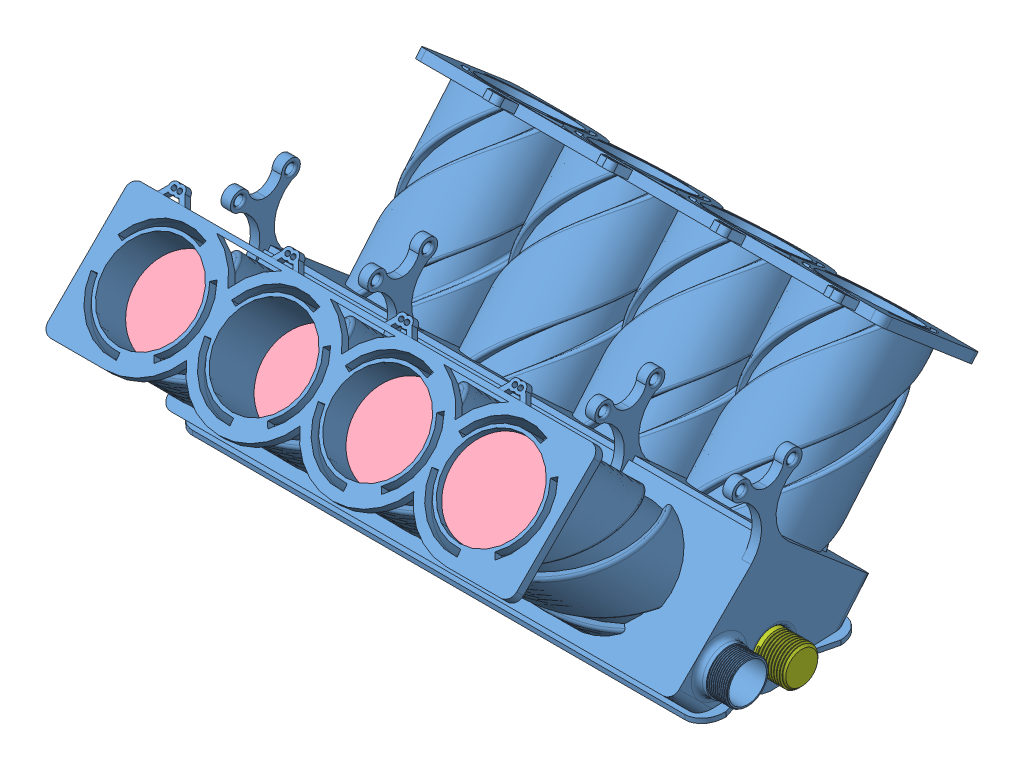
SolidWorks assembly Full Crank, configuration Default. Lengths in mm.
Overall size (601.48 350.14 484.53).
151 component instances, 27 part files, 63 mates.
Components (placement in the parent):
- exhuast Left-1: exhuast Left [Default<As Machined>] at (-44.5302 479.4245 -557.6035) x (1 0 0) z (0 0.648313 0.761374) size (550 292.5 196.99) (hidden)
- exhuast Right-1: exhuast Right [Default<As Machined>] at (-105.0302 606.7426 -177.23) x (1 0 0) z (0 -0.707107 0.707107) size (550 292.5 196.99) (hidden)
- Engine full-1: Engine full [Default] at (257.949 54.9062 -9.1227) x (-1 0 0) z (0 0.079946 -0.996799) size (581.5 289.56 459.4)
- AirRailsFinal-1: AirRailsFinal [Default] at (-30.5697 195.6323 -202.0466) x (1 0 0) z (0 0 1) size (435.48 82.44 318.32) (hidden)
- supercharger-1: supercharger [Default] at (314.7583 907.7189 -431.8002) x (0 0 1) z (0 -1 0) size (226 539.76 151) (hidden)
  - casing-1: casing [Default] at (105.1186 33.7762 242.5866) size (226 360 151)
  - cork screw one-1: cork screw one [Default] at (180.1186 333.7762 242.5866) x (0.113215 0 0.993571) z (-0.993571 0 0.113215) size (101.97 371 100.73)
  - cork screw two-1: cork screw two [Default] at (105.1186 33.7762 242.5866) x (-0.675443 0 -0.737412) z (0.737412 0 -0.675443) size (99.6 341 99.85)
  - LidOne-1: LidOne [Default] at (180.1186 28.7762 242.5866) x (-1 0 0) z (0 0 1) size (226 23.47 151)
  - heligearAntiClockwise-1: heligearAntiClockwise [Default] at (180.1186 339.7762 242.5866) x (-0.760972 0 0.648785) z (-0.648785 0 -0.760972) size (76.65 15 76.65)
  - heligearClockwise-1: heligearClockwise [Default] at (105.1186 339.7762 242.5866) x (-0.120243 0 0.992744) z (-0.992744 0 -0.120243) size (76.65 15 76.65)
  - axle support-2: axle support [Default] at (126.5104 354.7762 251.6132) size (28.48 5 80.98)
  - heligearAntiClockwise 38mm-1: heligearAntiClockwise 38mm [Default] at (180.1186 359.7762 242.5866) x (0.451037 0 0.892505) z (-0.892505 0 0.451037) size (40.05 20 40.06)
  - heligearClockwise 38mm-1: heligearClockwise 38mm [Default] at (142.6186 359.7762 242.5885) x (0.774286 0 0.632836) z (-0.632836 0 0.774286) size (40.05 15 40.06)
  - PTaxle-1: PTaxle [Default] at (142.6186 357.7762 242.5885) x (0.987746 0 -0.156068) z (0.156068 0 0.987746) size (25 190.76 25)
  - LidGearSide-1: LidGearSide [Default] at (105.1186 388.7762 242.5866) size (226 108.1 151)
  - long bolts-20: long bolts [Default] at (79.8615 14.7762 303.5627) x (0 1 0) z (0 0 1) size (388.15 12.67 12.66)
  - long bolts-21: long bolts [Default] at (226.7877 14.7762 195.9176) x (0 1 0) z (0 0 1) size (388.15 12.67 12.66)
  - long bolts-22: long bolts [Default] at (205.3757 14.7762 181.6106) x (0 1 0) z (0 0 1) size (388.15 12.67 12.66)
  - long bolts-23: long bolts [Default] at (180.1186 14.7762 176.5866) x (0 1 0) z (0 0 1) size (388.15 12.67 12.66)
  - long bolts-24: long bolts [Default] at (105.1186 14.7762 176.5866) x (0 1 0) z (0 0 1) size (388.15 12.67 12.66)
  - long bolts-25: long bolts [Default] at (79.8615 14.7762 181.6106) x (0 1 0) z (0 0 1) size (388.15 12.67 12.66)
  - long bolts-26: long bolts [Default] at (58.4496 14.7762 195.9176) x (0 1 0) z (0 0 1) size (388.15 12.67 12.66)
  - long bolts-27: long bolts [Default] at (44.1426 14.7762 217.3295) x (0 1 0) z (0 0 1) size (388.15 12.67 12.66)
  - long bolts-28: long bolts [Default] at (39.1186 14.7762 242.5866) x (0 1 0) z (0 0 1) size (388.15 12.67 12.66)
  - long bolts-29: long bolts [Default] at (44.1426 14.7762 267.8437) x (0 1 0) z (0 0 1) size (388.15 12.67 12.66)
  - long bolts-30: long bolts [Default] at (58.4496 14.7762 289.2557) x (0 1 0) z (0 0 1) size (388.15 12.67 12.66)
  - long bolts-32: long bolts [Default] at (241.0947 14.7762 217.3295) x (0 1 0) z (0.991179 0 -0.132529) size (388.15 12.67 12.66)
  - long bolts-33: long bolts [Default] at (246.1186 14.7762 242.5866) x (0 1 0) z (0.903937 0 0.427666) size (388.15 12.67 12.66)
  - long bolts-34: long bolts [Default] at (241.0947 14.7762 267.8437) x (0 1 0) z (-0.949196 0 -0.314684) size (388.15 12.67 12.66)
  - long bolts-35: long bolts [Default] at (226.7877 14.7762 289.2557) x (0 1 0) z (-0.597909 0 0.801564) size (388.15 12.67 12.66)
  - long bolts-36: long bolts [Default] at (205.3757 14.7762 303.5627) x (0 1 0) z (-0.95126 0 -0.308391) size (388.15 12.67 12.66)
  - Nut 6mm-17: Nut 6mm [Default] at (205.3757 17.7762 303.5627) size (12 6 13.86)
  - Nut 6mm-18: Nut 6mm [Default] at (226.7877 17.7762 289.2557) size (12 6 13.86)
  - Nut 6mm-20: Nut 6mm [Default] at (241.0947 17.7762 217.3295) size (12 6 13.86)
  - Nut 6mm-21: Nut 6mm [Default] at (226.7877 17.7762 195.9176) size (12 6 13.86)
  - Nut 6mm-22: Nut 6mm [Default] at (241.0947 17.7762 267.8437) x (0.907106 0 -0.420902) z (0.420902 0 0.907106) size (12 6 13.86)
  - Nut 6mm-23: Nut 6mm [Default] at (246.1186 17.7762 242.5866) size (12 6 13.86)
  - Nut 6mm-24: Nut 6mm [Default] at (205.3757 17.7762 181.6106) size (12 6 13.86)
  - Nut 6mm-25: Nut 6mm [Default] at (105.1186 17.7762 176.5866) size (12 6 13.86)
  - Nut 6mm-26: Nut 6mm [Default] at (180.1186 17.7762 176.5866) size (12 6 13.86)
  - Nut 6mm-27: Nut 6mm [Default] at (79.8615 17.7762 303.5627) size (12 6 13.86)
  - Nut 6mm-29: Nut 6mm [Default] at (44.1426 17.7762 217.3295) size (12 6 13.86)
  - Nut 6mm-30: Nut 6mm [Default] at (79.8615 17.7762 181.6106) size (12 6 13.86)
  - Nut 6mm-31: Nut 6mm [Default] at (58.4496 17.7762 195.9176) size (12 6 13.86)
  - Nut 6mm-32: Nut 6mm [Default] at (44.1426 17.7762 267.8437) size (12 6 13.86)
  - Nut 6mm-33: Nut 6mm [Default] at (39.1186 17.7762 242.5866) size (12 6 13.86)
  - Nut 6mm-34: Nut 6mm [Default] at (58.4496 17.7762 289.2557) size (12 6 13.86)
- HeadASSEM-1: HeadASSEM [Default] at (236.3876 519.9383 1.112) x (-1 0 0) z (0 -0.648313 -0.761374) size (495 98 155) (hidden)
  - head-1: head [Default] at (-68.8322 296.3763 369.1572) size (495 90 155)
  - sparkplug-1: sparkplug [Default] at (38.6678 341.5148 336.6572) x (-0.837169 0 -0.546944) z (-0.546944 0 0.837169) size (16 84.49 18.48)
  - sparkplug-2: sparkplug [Default] at (158.6678 341.5148 336.6572) x (-0.837169 0 -0.546944) z (-0.546944 0 0.837169) size (16 84.49 18.48)
  - sparkplug-3: sparkplug [Default] at (278.6678 341.5148 336.6572) x (-0.837169 0 -0.546944) z (-0.546944 0 0.837169) size (16 84.49 18.48)
  - sparkplug-4: sparkplug [Default] at (-81.3322 341.5148 336.6572) x (-0.837169 0 -0.546944) z (-0.546944 0 0.837169) size (16 84.49 18.48)
  - campin-1: campin [Default] at (31.1678 376.3763 369.1572) x (-0.693491 0 -0.720466) z (0.720466 0 -0.693491) size (28 70 28)
  - campin-2: campin [Default] at (-48.8322 376.3763 369.1572) x (-0.717846 0 0.696202) z (-0.696202 0 -0.717846) size (28 70 28)
  - campin-3: campin [Default] at (151.1678 376.3763 369.1572) x (0.967975 0 -0.251048) z (0.251048 0 0.967975) size (28 70 28)
  - campin-4: campin [Default] at (71.1678 376.3763 369.1572) x (-0.768196 0 0.640214) z (-0.640214 0 -0.768196) size (28 70 28)
  - campin-6: campin [Default] at (-88.8322 376.3763 369.1572) x (0.884294 0 0.46693) z (-0.46693 0 0.884294) size (28 70 28)
  - campin-5: campin [Default] at (191.1678 376.3763 369.1572) x (0.919682 0 -0.392664) z (0.392664 0 0.919682) size (28 70 28)
  - campin-7: campin [Default] at (271.1678 376.3763 369.1572) x (0.288066 0 0.95761) z (-0.95761 0 0.288066) size (28 70 28)
  - campin-8: campin [Default] at (311.1678 376.3763 369.1572) x (0 0 1) z (-1 0 0) size (28 70 28)
  - cover-2: cover [Default] at (49.7609 309.3868 195.7023) size (495 63 135)
- HeadASSEM-2: HeadASSEM [Default] at (-25.948 543.3016 -582.4258) x (1 0 0) z (0 -0.707107 0.707107) size (495 98 155) (hidden)
  - head-1: head [Default] at (-68.8322 296.3763 369.1572) size (495 90 155)
  - sparkplug-1: sparkplug [Default] at (38.6678 341.5148 336.6572) x (-0.837169 0 -0.546944) z (-0.546944 0 0.837169) size (16 84.49 18.48)
  - sparkplug-2: sparkplug [Default] at (158.6678 341.5148 336.6572) x (-0.837169 0 -0.546944) z (-0.546944 0 0.837169) size (16 84.49 18.48)
  - sparkplug-3: sparkplug [Default] at (278.6678 341.5148 336.6572) x (-0.837169 0 -0.546944) z (-0.546944 0 0.837169) size (16 84.49 18.48)
  - sparkplug-4: sparkplug [Default] at (-81.3322 341.5148 336.6572) x (-0.837169 0 -0.546944) z (-0.546944 0 0.837169) size (16 84.49 18.48)
  - campin-1: campin [Default] at (31.1678 376.3763 369.1572) x (-0.693491 0 -0.720466) z (0.720466 0 -0.693491) size (28 70 28)
  - campin-2: campin [Default] at (-48.8322 376.3763 369.1572) x (-0.717846 0 0.696202) z (-0.696202 0 -0.717846) size (28 70 28)
  - campin-3: campin [Default] at (151.1678 376.3763 369.1572) x (0.967975 0 -0.251048) z (0.251048 0 0.967975) size (28 70 28)
  - campin-4: campin [Default] at (71.1678 376.3763 369.1572) x (-0.768196 0 0.640214) z (-0.640214 0 -0.768196) size (28 70 28)
  - campin-6: campin [Default] at (-88.8322 376.3763 369.1572) x (0.884294 0 0.46693) z (-0.46693 0 0.884294) size (28 70 28)
  - campin-5: campin [Default] at (191.1678 376.3763 369.1572) x (0.919682 0 -0.392664) z (0.392664 0 0.919682) size (28 70 28)
  - campin-7: campin [Default] at (271.1678 376.3763 369.1572) x (0.288066 0 0.95761) z (-0.95761 0 0.288066) size (28 70 28)
  - campin-8: campin [Default] at (311.1678 376.3763 369.1572) x (0 0 1) z (-1 0 0) size (28 70 28)
  - cover-2: cover [Default] at (49.7609 309.3868 195.7023) size (495 63 135)
- piston-17: piston [Default] at (-109.277 481.1421 -88.3189) x (0.173277 -0.365674 0.914471) z (0.983439 0.014146 -0.180689) size (135.16 260.35 112.46) (flexible)
  - C clip 6mm inner, 12mm outer-1: C clip 6mm inner, 12mm outer [Default] at (-54.593 75.297 36.5632) x (0.984863 0.004767 -0.173271) z (0.004519 0.998576 0.053159) size (12 2 10.86)
  - conrod-1: conrod [Default] at (-50.1744 73.942 61.6409) x (-0.720039 -0.688113 0.089688) z (0.173277 -0.053137 0.983439) size (10 10 67)
  - piston head-1: piston head [Default] at (-40.0688 38.2448 23.8674) x (0.173277 -0.053137 0.983439) z (0.905199 0.402038 -0.137769) size (94 60 94)
  - C clip 6mm inner, 12mm outer-2: C clip 6mm inner, 12mm outer [Default] at (-57.0189 76.0409 22.795) x (0.223524 0.974608 0.013276) z (-0.959173 0.217522 0.180755) size (12 2 10.86)
  - C clip 6mm inner, 12mm outer-3: C clip 6mm inner, 12mm outer [Default] at (-60.7444 77.1834 1.6511) x (0.97149 0.173277 -0.16181) z (-0.16181 0.983439 0.081647) size (12 2 10.86)
  - C clip 6mm inner, 12mm outer-4: C clip 6mm inner, 12mm outer [Default] at (-50.8675 74.1546 57.7071) x (0.97149 0.173277 -0.16181) z (-0.16181 0.983439 0.081647) size (12 2 10.86)
  - piston rod-2: piston rod [Default] at (-54.9396 75.4033 34.5963) x (0.955086 0.252791 -0.154623) z (-0.240388 0.966061 0.094553) size (39.11 12.84 199.57)
  - pistoncaps-2: pistoncaps [Default] at (-55.6848 78.3981 34.8894) x (0.955086 0.252791 -0.154623) z (-0.240388 0.966061 0.094553) size (39.11 12.23 13.87)
- piston-18: piston [Default] at (-69.2771 511.7348 -444.9973) x (0.173277 0.88231 0.437612) z (0.983439 -0.17898 -0.028546) size (166.8 251.73 112.46) (flexible)
  - C clip 6mm inner, 12mm outer-1: C clip 6mm inner, 12mm outer [Default] at (-54.593 75.297 36.5632) x (0.984863 0.004767 -0.173271) z (0.004519 0.998576 0.053159) size (12 2 10.86)
  - conrod-1: conrod [Default] at (-50.1744 73.942 61.6409) x (-0.720039 -0.688113 0.089688) z (0.173277 -0.053137 0.983439) size (10 10 67)
  - piston head-1: piston head [Default] at (-40.0688 38.2448 23.8674) x (0.173277 -0.053137 0.983439) z (0.905199 0.402038 -0.137769) size (94 60 94)
  - C clip 6mm inner, 12mm outer-2: C clip 6mm inner, 12mm outer [Default] at (-57.0189 76.0409 22.795) x (0.223524 0.974608 0.013276) z (-0.959173 0.217522 0.180755) size (12 2 10.86)
  - C clip 6mm inner, 12mm outer-3: C clip 6mm inner, 12mm outer [Default] at (-60.7444 77.1834 1.6511) x (0.97149 0.173277 -0.16181) z (-0.16181 0.983439 0.081647) size (12 2 10.86)
  - C clip 6mm inner, 12mm outer-4: C clip 6mm inner, 12mm outer [Default] at (-50.8675 74.1546 57.7071) x (0.97149 0.173277 -0.16181) z (-0.16181 0.983439 0.081647) size (12 2 10.86)
  - piston rod-2: piston rod [Default] at (-54.9396 75.4033 34.5963) x (0.899295 0.415661 -0.135993) z (-0.40155 0.907966 0.11981) size (39.11 12.84 199.57)
  - pistoncaps-2: pistoncaps [Default] at (-56.1844 78.218 34.9677) x (0.899295 0.415661 -0.135993) z (-0.40155 0.907966 0.11981) size (39.11 12.23 13.87)
- piston-19: piston [Default] at (50.7229 534.7253 -464.5739) x (0.173277 0.88231 0.437612) z (0.983439 -0.17898 -0.028546) size (191.04 240.07 112.46) (flexible)
  - C clip 6mm inner, 12mm outer-1: C clip 6mm inner, 12mm outer [Default] at (-54.593 75.297 36.5632) x (0.984863 0.004767 -0.173271) z (0.004519 0.998576 0.053159) size (12 2 10.86)
  - conrod-1: conrod [Default] at (-50.1744 73.942 61.6409) x (-0.720039 -0.688113 0.089688) z (0.173277 -0.053137 0.983439) size (10 10 67)
  - piston head-1: piston head [Default] at (-40.0688 38.2448 23.8674) x (0.173277 -0.053137 0.983439) z (0.905199 0.402038 -0.137769) size (94 60 94)
  - C clip 6mm inner, 12mm outer-2: C clip 6mm inner, 12mm outer [Default] at (-57.0189 76.0409 22.795) x (0.223524 0.974608 0.013276) z (-0.959173 0.217522 0.180755) size (12 2 10.86)
  - C clip 6mm inner, 12mm outer-3: C clip 6mm inner, 12mm outer [Default] at (-60.7444 77.1834 1.6511) x (0.97149 0.173277 -0.16181) z (-0.16181 0.983439 0.081647) size (12 2 10.86)
  - C clip 6mm inner, 12mm outer-4: C clip 6mm inner, 12mm outer [Default] at (-50.8675 74.1546 57.7071) x (0.97149 0.173277 -0.16181) z (-0.16181 0.983439 0.081647) size (12 2 10.86)
  - piston rod-2: piston rod [Default] at (-54.9396 75.4033 34.5963) x (0.831756 0.542622 -0.117233) z (-0.527406 0.838294 0.138221) size (39.11 12.84 199.57)
  - pistoncaps-2: pistoncaps [Default] at (-56.5745 78.002 35.0248) x (0.831756 0.542622 -0.117233) z (-0.527406 0.838294 0.138221) size (39.11 12.23 13.87)
- piston-20: piston [Default] at (39.7166 499.6483 -138.2114) x (-0.173277 0.914471 -0.365674) z (-0.983439 -0.180689 0.014146) size (159.48 254.33 112.46) (flexible)
  - C clip 6mm inner, 12mm outer-1: C clip 6mm inner, 12mm outer [Default] at (-54.593 75.297 36.5632) x (0.984863 0.004767 -0.173271) z (0.004519 0.998576 0.053159) size (12 2 10.86)
  - conrod-1: conrod [Default] at (-50.1744 73.942 61.6409) x (-0.720039 -0.688113 0.089688) z (0.173277 -0.053137 0.983439) size (10 10 67)
  - piston head-1: piston head [Default] at (-40.0688 38.2448 23.8674) x (0.173277 -0.053137 0.983439) z (0.905199 0.402038 -0.137769) size (94 60 94)
  - C clip 6mm inner, 12mm outer-2: C clip 6mm inner, 12mm outer [Default] at (-57.0189 76.0409 22.795) x (0.223524 0.974608 0.013276) z (-0.959173 0.217522 0.180755) size (12 2 10.86)
  - C clip 6mm inner, 12mm outer-3: C clip 6mm inner, 12mm outer [Default] at (-60.7444 77.1834 1.6511) x (0.97149 0.173277 -0.16181) z (-0.16181 0.983439 0.081647) size (12 2 10.86)
  - C clip 6mm inner, 12mm outer-4: C clip 6mm inner, 12mm outer [Default] at (-50.8675 74.1546 57.7071) x (0.97149 0.173277 -0.16181) z (-0.16181 0.983439 0.081647) size (12 2 10.86)
  - piston rod-2: piston rod [Default] at (-54.9396 75.4033 34.5963) x (0.915142 0.37773 -0.140834) z (-0.363991 0.92439 0.11408) size (39.11 12.84 199.57)
  - pistoncaps-2: pistoncaps [Default] at (-56.0679 78.2689 34.95) x (0.915142 0.37773 -0.140834) z (-0.363991 0.92439 0.11408) size (39.11 12.23 13.87)
- piston-21: piston [Default] at (159.7166 522.5544 -115.3053) x (-0.173277 0.914471 -0.365674) z (-0.983439 -0.180689 0.014146) size (135.38 260.31 112.46) (flexible)
  - C clip 6mm inner, 12mm outer-1: C clip 6mm inner, 12mm outer [Default] at (-54.593 75.297 36.5632) x (0.984863 0.004767 -0.173271) z (0.004519 0.998576 0.053159) size (12 2 10.86)
  - conrod-1: conrod [Default] at (-50.1744 73.942 61.6409) x (-0.720039 -0.688113 0.089688) z (0.173277 -0.053137 0.983439) size (10 10 67)
  - piston head-1: piston head [Default] at (-40.0688 38.2448 23.8674) x (0.173277 -0.053137 0.983439) z (0.905199 0.402038 -0.137769) size (94 60 94)
  - C clip 6mm inner, 12mm outer-2: C clip 6mm inner, 12mm outer [Default] at (-57.0189 76.0409 22.795) x (0.223524 0.974608 0.013276) z (-0.959173 0.217522 0.180755) size (12 2 10.86)
  - C clip 6mm inner, 12mm outer-3: C clip 6mm inner, 12mm outer [Default] at (-60.7444 77.1834 1.6511) x (0.97149 0.173277 -0.16181) z (-0.16181 0.983439 0.081647) size (12 2 10.86)
  - C clip 6mm inner, 12mm outer-4: C clip 6mm inner, 12mm outer [Default] at (-50.8675 74.1546 57.7071) x (0.97149 0.173277 -0.16181) z (-0.16181 0.983439 0.081647) size (12 2 10.86)
  - piston rod-2: piston rod [Default] at (-54.9396 75.4033 34.5963) x (0.954801 0.253932 -0.154511) z (-0.241516 0.965761 0.094736) size (39.11 12.84 199.57)
  - pistoncaps-2: pistoncaps [Default] at (-55.6883 78.3971 34.89) x (0.954801 0.253932 -0.154511) z (-0.241516 0.965761 0.094736) size (39.11 12.23 13.87)
- piston-23: piston [Default] at (279.7166 541.4571 -96.4026) x (-0.173277 0.914471 -0.365674) z (-0.983439 -0.180689 0.014146) size (169 250.87 112.46) (flexible)
  - C clip 6mm inner, 12mm outer-1: C clip 6mm inner, 12mm outer [Default] at (-54.593 75.297 36.5632) x (0.984863 0.004767 -0.173271) z (0.004519 0.998576 0.053159) size (12 2 10.86)
  - conrod-1: conrod [Default] at (-50.1744 73.942 61.6409) x (-0.720039 -0.688113 0.089688) z (0.173277 -0.053137 0.983439) size (10 10 67)
  - piston head-1: piston head [Default] at (-40.0688 38.2448 23.8674) x (0.173277 -0.053137 0.983439) z (0.905199 0.402038 -0.137769) size (94 60 94)
  - C clip 6mm inner, 12mm outer-2: C clip 6mm inner, 12mm outer [Default] at (-57.0189 76.0409 22.795) x (0.223524 0.974608 0.013276) z (-0.959173 0.217522 0.180755) size (12 2 10.86)
  - C clip 6mm inner, 12mm outer-3: C clip 6mm inner, 12mm outer [Default] at (-60.7444 77.1834 1.6511) x (0.97149 0.173277 -0.16181) z (-0.16181 0.983439 0.081647) size (12 2 10.86)
  - C clip 6mm inner, 12mm outer-4: C clip 6mm inner, 12mm outer [Default] at (-50.8675 74.1546 57.7071) x (0.97149 0.173277 -0.16181) z (-0.16181 0.983439 0.081647) size (12 2 10.86)
  - piston rod-2: piston rod [Default] at (-54.9396 75.4033 34.5963) x (0.894142 0.427118 -0.134466) z (-0.412899 0.902633 0.121522) size (39.11 12.84 199.57)
  - pistoncaps-2: pistoncaps [Default] at (-56.2195 78.2015 34.973) x (0.894142 0.427118 -0.134466) z (-0.412899 0.902633 0.121522) size (39.11 12.23 13.87)
- piston-25: piston [Default] at (319.7166 499.2807 -497.9162) x (-0.173277 -0.291394 -0.940779) z (-0.983439 -0.000345 0.181241) size (190.85 240.18 112.46) (flexible)
  - C clip 6mm inner, 12mm outer-1: C clip 6mm inner, 12mm outer [Default] at (-54.593 75.297 36.5632) x (0.984863 0.004767 -0.173271) z (0.004519 0.998576 0.053159) size (12 2 10.86)
  - conrod-1: conrod [Default] at (-50.1744 73.942 61.6409) x (-0.720039 -0.688113 0.089688) z (0.173277 -0.053137 0.983439) size (10 10 67)
  - piston head-1: piston head [Default] at (-40.0688 38.2448 23.8674) x (0.173277 -0.053137 0.983439) z (0.905199 0.402038 -0.137769) size (94 60 94)
  - C clip 6mm inner, 12mm outer-2: C clip 6mm inner, 12mm outer [Default] at (-57.0189 76.0409 22.795) x (0.223524 0.974608 0.013276) z (-0.959173 0.217522 0.180755) size (12 2 10.86)
  - C clip 6mm inner, 12mm outer-3: C clip 6mm inner, 12mm outer [Default] at (-60.7444 77.1834 1.6511) x (0.97149 0.173277 -0.16181) z (-0.16181 0.983439 0.081647) size (12 2 10.86)
  - C clip 6mm inner, 12mm outer-4: C clip 6mm inner, 12mm outer [Default] at (-50.8675 74.1546 57.7071) x (0.97149 0.173277 -0.16181) z (-0.16181 0.983439 0.081647) size (12 2 10.86)
  - piston rod-2: piston rod [Default] at (-54.9396 75.4033 34.5963) x (0.832379 0.541631 -0.117396) z (-0.526423 0.838935 0.138083) size (39.11 12.84 199.57)
  - pistoncaps-2: pistoncaps [Default] at (-56.5715 78.004 35.0244) x (0.832379 0.541631 -0.117396) z (-0.526423 0.838935 0.138083) size (39.11 12.23 13.87)
- piston-26: piston [Default] at (199.7166 525.8781 -520.564) x (-0.173277 -0.291394 -0.940779) z (-0.983439 -0.000345 0.181241) size (166.6 251.81 112.46) (flexible)
  - C clip 6mm inner, 12mm outer-1: C clip 6mm inner, 12mm outer [Default] at (-54.593 75.297 36.5632) x (0.984863 0.004767 -0.173271) z (0.004519 0.998576 0.053159) size (12 2 10.86)
  - conrod-1: conrod [Default] at (-50.1744 73.942 61.6409) x (-0.720039 -0.688113 0.089688) z (0.173277 -0.053137 0.983439) size (10 10 67)
  - piston head-1: piston head [Default] at (-40.0688 38.2448 23.8674) x (0.173277 -0.053137 0.983439) z (0.905199 0.402038 -0.137769) size (94 60 94)
  - C clip 6mm inner, 12mm outer-2: C clip 6mm inner, 12mm outer [Default] at (-57.0189 76.0409 22.795) x (0.223524 0.974608 0.013276) z (-0.959173 0.217522 0.180755) size (12 2 10.86)
  - C clip 6mm inner, 12mm outer-3: C clip 6mm inner, 12mm outer [Default] at (-60.7444 77.1834 1.6511) x (0.97149 0.173277 -0.16181) z (-0.16181 0.983439 0.081647) size (12 2 10.86)
  - C clip 6mm inner, 12mm outer-4: C clip 6mm inner, 12mm outer [Default] at (-50.8675 74.1546 57.7071) x (0.97149 0.173277 -0.16181) z (-0.16181 0.983439 0.081647) size (12 2 10.86)
  - piston rod-2: piston rod [Default] at (-54.9396 75.4033 34.5963) x (0.899763 0.414601 -0.136133) z (-0.400501 0.908451 0.119652) size (39.11 12.84 199.57)
  - pistoncaps-2: pistoncaps [Default] at (-56.1811 78.2195 34.9672) x (0.899763 0.414601 -0.136133) z (-0.400501 0.908451 0.119652) size (39.11 12.23 13.87)
- Full Crank-1: Full Crank [Default] at (0 694.6813 -470.8641) x (1 0 0) z (0 0.35823 -0.933633) size (600 79.88 79.88)
Mates (geometry in assembly coordinates):
- Concentric48: concentric aligned: cylinder of Engine full-1 through (-94.7802 353.9519 -249.7084) axis (0 0.707107 0.707107) radius 47.5; cylinder of piston-17/piston head-1 through (-94.7802 460.5398 -143.1205) axis (0 0.707107 0.707107) radius 47
- Concentric53: concentric: cylinder of ? through (-87.7802 343.0219 -298.445) axis (-1 0 0) radius 10; cylinder of piston-17/piston rod-2 through (-100.7802 279.2233 -282.4688) axis (1 0 0) radius 10
- Concentric54: concentric: cylinder of Engine full-1 through (406.7008 318.0336 -299.2083) axis (-1 0 0) radius 20; cylinder of ? through (-120.7802 318.0336 -299.2083) axis (1 0 0) radius 20
- Distance10: distance = 8 mm: plane of ? through (-108.7802 318.0336 -299.2083) normal (1 0 0); plane of piston-17/pistoncaps-2 through (-100.7802 429.0381 -173.9307) normal (-1 0 0)
- Concentric55: concentric aligned: cylinder of Engine full-1 through (-94.7802 353.9519 -249.7084) axis (0 0.707107 0.707107) radius 47.5; cylinder of piston-17/piston head-1 through (-94.7802 460.5398 -143.1205) axis (0 0.707107 0.707107) radius 47
- Concentric56: concentric aligned: cylinder of Engine full-1 through (-54.7802 357.7943 -345.6782) axis (0 0.761374 -0.648313) radius 47.5; cylinder of piston-18/piston head-1 through (-54.7802 455.4615 -428.8422) axis (0 0.761374 -0.648313) radius 47
- Concentric57: concentric aligned: cylinder of Engine full-1 through (25.2198 353.9519 -249.7085) axis (0 0.707107 0.707107) radius 47.5; cylinder of piston-20/piston head-1 through (25.2198 444.8467 -158.8137) axis (0 0.707107 0.707107) radius 47
- Concentric58: concentric aligned: cylinder of Engine full-1 through (65.2198 357.7943 -345.6782) axis (0 0.761374 -0.648313) radius 47.5; cylinder of piston-19/piston head-1 through (65.2198 478.4521 -448.4188) axis (0 0.761374 -0.648313) radius 47
- Concentric59: concentric aligned: cylinder of Engine full-1 through (145.2198 353.9519 -249.7085) axis (0 0.707107 0.707107) radius 47.5; cylinder of piston-21/piston head-1 through (145.2198 467.7528 -135.9076) axis (0 0.707107 0.707107) radius 47
- Concentric61: concentric aligned: cylinder of Engine full-1 through (265.2198 353.9519 -249.7085) axis (0 0.707107 0.707107) radius 47.5; cylinder of piston-23/piston head-1 through (265.2198 486.6555 -117.0049) axis (0 0.707107 0.707107) radius 47
- Concentric62: concentric aligned: cylinder of Engine full-1 through (305.2198 357.7943 -345.6782) axis (0 0.761374 -0.648313) radius 47.5; cylinder of piston-25/piston head-1 through (305.2198 474.3632 -444.9371) axis (0 0.761374 -0.648313) radius 47
- Concentric63: concentric aligned: cylinder of Engine full-1 through (185.2198 357.7943 -345.6782) axis (0 0.761374 -0.648313) radius 47.5; cylinder of piston-26/piston head-1 through (185.2198 500.9606 -467.5848) axis (0 0.761374 -0.648313) radius 47
- Concentric64: concentric anti-aligned: cylinder of piston-17/pistoncaps-2 through (-100.7802 279.2233 -282.4688) axis (1 0 0) radius 10; cylinder of ? through (-87.7802 313.913 -271.5645) axis (-1 0 0) radius 10
- Concentric65: concentric aligned: cylinder of piston-18/piston rod-2 through (-60.7802 279.2233 -282.4688) axis (1 0 0) radius 10; cylinder of ? through (-61.7802 331.9406 -309.9703) axis (1 0 0) radius 10
- Distance11: distance = 8 mm: plane of ? through (-108.7802 303.7239 -299.7812) normal (1 0 0); plane of piston-17/pistoncaps-2 through (-100.7802 429.0381 -173.9307) normal (-1 0 0)
- Concentric66: concentric: cylinder of Engine full-1 through (406.7008 303.7239 -299.7813) axis (-1 0 0) radius 20; cylinder of ? through (-120.7802 303.7239 -299.7812) axis (1 0 0) radius 20
- Parallel1: parallel aligned: plane of piston-23/piston head-1 through (292.7198 453.4215 -83.7709) normal (1 0 0); plane of piston-25/piston head-1 through (332.7198 504.8339 -409.1525) normal (1 0 0)
- Parallel2: parallel aligned: plane of piston-21/piston head-1 through (172.7198 434.5188 -102.6736) normal (1 0 0); plane of piston-23/piston head-1 through (292.7198 453.4215 -83.7709) normal (1 0 0)
- Parallel3: parallel anti-aligned: plane of piston-20/piston head-1 through (-2.2802 411.6127 -125.5797) normal (-1 0 0); plane of piston-21/piston head-1 through (172.7198 434.5188 -102.6736) normal (1 0 0)
- Parallel4: parallel aligned: plane of piston-17/piston head-1 through (-67.2802 493.7739 -176.3546) normal (1 0 0); plane of piston-20/piston head-1 through (52.7198 411.6127 -125.5797) normal (1 0 0)
- Parallel5: parallel aligned: plane of piston-25/piston head-1 through (332.7198 504.8339 -409.1525) normal (1 0 0); plane of piston-26/piston head-1 through (212.7198 531.4313 -431.8003) normal (1 0 0)
- Parallel6: parallel aligned: plane of piston-19/piston head-1 through (92.7198 447.9814 -484.2033) normal (1 0 0); plane of piston-26/piston head-1 through (212.7198 531.4313 -431.8003) normal (1 0 0)
- Parallel7: parallel aligned: plane of piston-18/piston head-1 through (-27.2802 424.9908 -464.6268) normal (1 0 0); plane of piston-19/piston head-1 through (92.7198 447.9814 -484.2033) normal (1 0 0)
- Concentric88: concentric aligned: cylinder of piston-17/pistoncaps-2 through (-100.7802 279.2233 -282.4688) axis (1 0 0) radius 10; cylinder of piston-18/pistoncaps-2 through (-60.7802 279.2233 -282.4688) axis (1 0 0) radius 10
- Concentric89: concentric anti-aligned: cylinder of piston-19/pistoncaps-2 through (59.2198 286.4115 -324.2819) axis (1 0 0) radius 10; cylinder of piston-20/pistoncaps-2 through (31.2198 286.4115 -324.2819) axis (-1 0 0) radius 10
- Concentric90: concentric aligned: cylinder of piston-21/pistoncaps-2 through (151.2198 328.2245 -317.0936) axis (-1 0 0) radius 10; cylinder of piston-26/pistoncaps-2 through (191.2198 328.2245 -317.0936) axis (-1 0 0) radius 10
- Concentric91: concentric aligned: cylinder of piston-23/pistoncaps-2 through (271.2198 321.0363 -275.2806) axis (-1 0 0) radius 10; cylinder of piston-25/pistoncaps-2 through (311.2198 321.0363 -275.2806) axis (-1 0 0) radius 10
- Concentric92: concentric anti-aligned: cylinder of piston-17/pistoncaps-2 through (-100.7802 279.2233 -282.4688) axis (1 0 0) radius 10; cylinder of ? through (-74.7802 326.7853 -318.9691) axis (-1 0 0) radius 10
- Distance17: distance = 7 mm: plane of ? through (-107.7802 303.7239 -299.7812) normal (1 0 0); plane of piston-17/pistoncaps-2 through (-100.7802 429.0381 -173.9307) normal (-1 0 0)
- Concentric100: concentric aligned: cylinder of Engine full-1 through (-94.7802 353.9519 -249.7084) axis (0 0.707107 0.707107) radius 47.5; cylinder of piston-17/piston head-1 through (-94.7802 460.5398 -143.1205) axis (0 0.707107 0.707107) radius 47
- Concentric101: concentric aligned: cylinder of Engine full-1 through (25.2198 353.9519 -249.7085) axis (0 0.707107 0.707107) radius 47.5; cylinder of piston-20/piston head-1 through (25.2198 444.8467 -158.8137) axis (0 0.707107 0.707107) radius 47
- Concentric102: concentric aligned: cylinder of Engine full-1 through (145.2198 353.9519 -249.7085) axis (0 0.707107 0.707107) radius 47.5; cylinder of piston-21/piston head-1 through (145.2198 467.7528 -135.9076) axis (0 0.707107 0.707107) radius 47
- Concentric103: concentric aligned: cylinder of Engine full-1 through (265.2198 353.9519 -249.7085) axis (0 0.707107 0.707107) radius 47.5; cylinder of piston-23/piston head-1 through (265.2198 486.6555 -117.0049) axis (0 0.707107 0.707107) radius 47
- Concentric104: concentric aligned: cylinder of Engine full-1 through (-54.7802 357.7943 -345.6782) axis (0 0.761374 -0.648313) radius 47.5; cylinder of piston-18/piston head-1 through (-54.7802 455.4615 -428.8422) axis (0 0.761374 -0.648313) radius 47
- Concentric105: concentric aligned: cylinder of Engine full-1 through (65.2198 357.7943 -345.6782) axis (0 0.761374 -0.648313) radius 47.5; cylinder of piston-19/piston head-1 through (65.2198 478.4521 -448.4188) axis (0 0.761374 -0.648313) radius 47
- Concentric106: concentric aligned: cylinder of Engine full-1 through (185.2198 357.7943 -345.6782) axis (0 0.761374 -0.648313) radius 47.5; cylinder of piston-26/piston head-1 through (185.2198 500.9606 -467.5848) axis (0 0.761374 -0.648313) radius 47
- Concentric107: concentric aligned: cylinder of Engine full-1 through (305.2198 357.7943 -345.6782) axis (0 0.761374 -0.648313) radius 47.5; cylinder of piston-25/piston head-1 through (305.2198 474.3632 -444.9371) axis (0 0.761374 -0.648313) radius 47
- Concentric108: concentric: cylinder of ? through (285.2198 303.7239 -299.7812) axis (-1 0 0) radius 20; cylinder of ? through (165.2198 303.7239 -299.7812) axis (1 0 0) radius 20
- Concentric109: concentric: cylinder of ? through (165.2198 303.7239 -299.7812) axis (-1 0 0) radius 20; cylinder of ? through (45.2198 303.7239 -299.7812) axis (1 0 0) radius 20
- Concentric110: concentric: cylinder of ? through (45.2198 303.7239 -299.7812) axis (-1 0 0) radius 20; cylinder of ? through (-74.7802 303.7239 -299.7812) axis (1 0 0) radius 20
- Coincident1: coincident: plane of ? through (-14.7802 303.7239 -299.7812) normal (-1 0 0); plane of ? through (-14.7802 303.7239 -299.7812) normal (1 0 0)
- Coincident2: coincident: plane of ? through (105.2198 303.7239 -299.7812) normal (-1 0 0); plane of ? through (105.2198 303.7239 -299.7812) normal (1 0 0)
- Coincident3: coincident: plane of ? through (225.2198 303.7239 -299.7812) normal (-1 0 0); plane of ? through (225.2198 303.7239 -299.7812) normal (1 0 0)
- Coincident4: coincident: plane of ? through (238.2198 288.609 -309.8857) normal (0 -0.831343 -0.55576); plane of ? through (212.2198 288.609 -309.8857) normal (0 -0.831343 -0.55576)
- Coincident5: coincident: plane of ? through (118.2198 293.6195 -284.6663) normal (0 -0.55576 0.831343); plane of ? through (92.2198 293.6195 -284.6663) normal (0 -0.55576 0.831343)
- Coincident6: coincident: plane of ? through (-1.7802 288.609 -309.8857) normal (0 -0.831343 -0.55576); plane of ? through (-27.7802 288.609 -309.8857) normal (0 -0.831343 -0.55576)
- Concentric111: concentric anti-aligned: cylinder of piston-25/pistoncaps-2 through (311.2198 321.0363 -275.2806) axis (-1 0 0) radius 10; cylinder of ? through (285.2198 278.7836 -316.454) axis (1 0 0) radius 10
- Distance18: distance = 7 mm anti-aligned: plane of piston-25/pistoncaps-2 through (311.2198 441.1344 -415.9983) normal (1 0 0); plane of ? through (318.2198 303.7239 -299.7813) normal (-1 0 0)
- Concentric112: concentric: cylinder of Engine full-1 through (406.7008 303.7239 -299.7813) axis (-1 0 0) radius 20; cylinder of ? through (285.2198 303.7239 -299.7812) axis (1 0 0) radius 20
- Concentric113: concentric anti-aligned: cylinder of piston-26/pistoncaps-2 through (191.2198 328.2245 -317.0936) axis (-1 0 0) radius 10; cylinder of ? through (165.2198 287.0511 -274.841) axis (1 0 0) radius 10
- Concentric114: concentric aligned: cylinder of piston-19/pistoncaps-2 through (59.2198 286.4115 -324.2819) axis (1 0 0) radius 10; cylinder of ? through (45.2198 328.6642 -283.1085) axis (1 0 0) radius 10
- Concentric115: concentric aligned: cylinder of piston-18/pistoncaps-2 through (-60.7802 279.2233 -282.4688) axis (1 0 0) radius 10; cylinder of ? through (-74.7802 320.3967 -324.7215) axis (1 0 0) radius 10
- Concentric117: concentric aligned: cylinder of Engine full-1 through (-54.7802 357.7943 -345.6782) axis (0 0.761374 -0.648313) radius 47.5; cylinder of piston-18/piston head-1 through (-54.7802 455.4615 -428.8422) axis (0 0.761374 -0.648313) radius 47
- Concentric118: concentric aligned: cylinder of Engine full-1 through (265.2198 353.9519 -249.7085) axis (0 0.707107 0.707107) radius 47.5; cylinder of piston-23/piston head-1 through (265.2198 486.6555 -117.0049) axis (0 0.707107 0.707107) radius 47
- Concentric119: concentric aligned: cylinder of Engine full-1 through (145.2198 353.9519 -249.7085) axis (0 0.707107 0.707107) radius 47.5; cylinder of piston-21/piston head-1 through (145.2198 467.7528 -135.9076) axis (0 0.707107 0.707107) radius 47
- Concentric120: concentric aligned: cylinder of Engine full-1 through (-94.7802 353.9519 -249.7084) axis (0 0.707107 0.707107) radius 47.5; cylinder of piston-17/piston head-1 through (-94.7802 460.5398 -143.1205) axis (0 0.707107 0.707107) radius 47
- Concentric121: concentric aligned: cylinder of Engine full-1 through (65.2198 357.7943 -345.6782) axis (0 0.761374 -0.648313) radius 47.5; cylinder of piston-19/piston head-1 through (65.2198 478.4521 -448.4188) axis (0 0.761374 -0.648313) radius 47
- Concentric123: concentric: cylinder of assembly; cylinder of Engine full-1 through (406.7008 303.7239 -299.7813) axis (-1 0 0) radius 20; cylinder of Full Crank-1 through (-74.7802 303.7239 -299.7812) axis (-1 0 0) radius 20
- Distance19: distance = 7 mm anti-aligned: plane of piston-17/pistoncaps-2 through (-100.7802 429.0381 -173.9307) normal (-1 0 0); plane of Full Crank-1 through (-107.7802 303.7239 -299.7812) normal (1 0 0)
- Concentric124: concentric anti-aligned: cylinder of piston-17/piston rod-2 through (-100.7802 279.2233 -282.4688) axis (1 0 0) radius 10; cylinder of Full Crank-1 through (-74.7802 279.2233 -282.4688) axis (-1 0 0) radius 10
- Concentric125: concentric aligned: cylinder of piston-20/piston rod-2 through (31.2198 286.4115 -324.2819) axis (-1 0 0) radius 10; cylinder of Full Crank-1 through (45.2198 286.4115 -324.2819) axis (-1 0 0) radius 10
- Concentric126: concentric aligned: cylinder of piston-21/piston rod-2 through (151.2198 328.2245 -317.0936) axis (-1 0 0) radius 10; cylinder of Full Crank-1 through (165.2198 328.2245 -317.0936) axis (-1 0 0) radius 10
- Concentric127: concentric aligned: cylinder of piston-23/piston rod-2 through (271.2198 321.0363 -275.2806) axis (-1 0 0) radius 10; cylinder of Full Crank-1 through (285.2198 321.0363 -275.2806) axis (-1 0 0) radius 10
